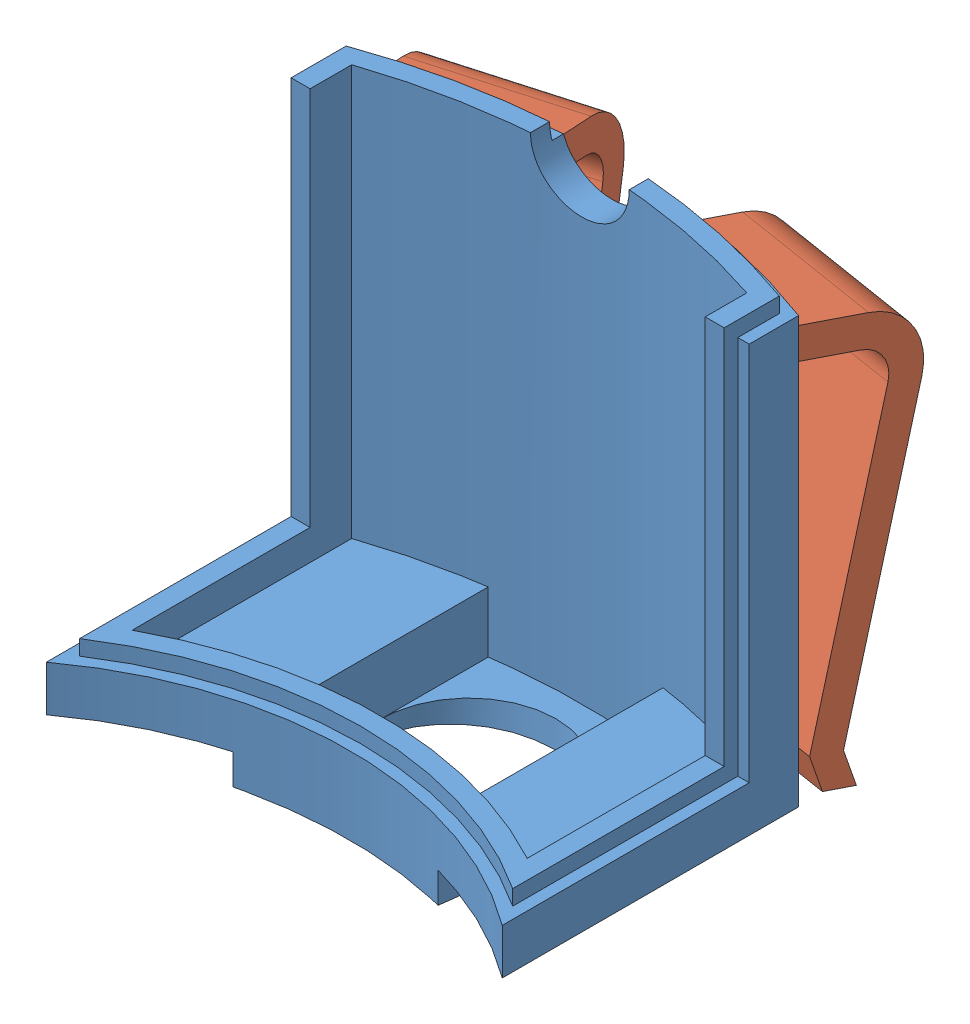
SolidWorks assembly support_bis_avec clips_2, configuration Default. Lengths in mm.
Overall size (32.17 33.18 31.36).
3 component instances, 2 part files, 6 mates.
Components (placement in the parent):
- support_pir_part1_bis-1: support_pir_part1_bis [Default] at (4.2891 3.4058 62.0234) size (30 33.18 22.24)
- clips-1: clips [Default] at (8.9906 4.0386 17.1366) x (0.155026 -0.224951 -0.961958) z (0.987262 0 0.159104) size (9.97 26.13 10)
- clips-3: clips [Default] at (-10.4956 4.0386 19.3813) x (-0.267704 -0.224951 -0.936873) z (0.961517 0 -0.274746) size (9.97 26.13 10)
Mates (geometry in assembly coordinates):
- Concentric1: concentric aligned: cylinder of support_pir_part1_bis-1 through (4.2891 5.4058 62.0234) axis (0 -1 0) radius 42.5; cylinder of clips-1 through (4.2891 31.2587 62.0234) axis (0 -1 0) radius 42.5
- Distance1: distance = 1 mm: line of support_pir_part1_bis-1 through (19.2891 31.4058 22.2585) axis (0 -1 0); line of clips-1 through (18.3493 30.1082 21.9166) axis (0 -1 0)
- Distance2: distance = 3 mm: line of support_pir_part1_bis-1 through (11.0391 -0.5942 20.0629) axis (-1 0 0); line of clips-1 through (18.9599 2.4058 18.1277) axis (-0.987262 0 -0.159104)
- Concentric2: concentric aligned: cylinder of support_pir_part1_bis-1 through (4.2891 5.4058 62.0234) axis (0 -1 0) radius 42.5; cylinder of clips-3 through (4.2891 31.2587 62.0234) axis (0 -1 0) radius 42.5
- Distance3: distance = 1 mm: line of clips-3 through (-9.7712 29.9712 21.9166) axis (0 -1 0); line of support_pir_part1_bis-1 through (-10.7109 31.4058 22.2585) axis (0 -1 0)
- Distance4: distance = 3 mm: line of clips-3 through (-1.0474 2.4058 16.0496) axis (-0.961517 0 0.274746); line of support_pir_part1_bis-1 through (11.0391 -0.5942 20.0629) axis (-1 0 0)
